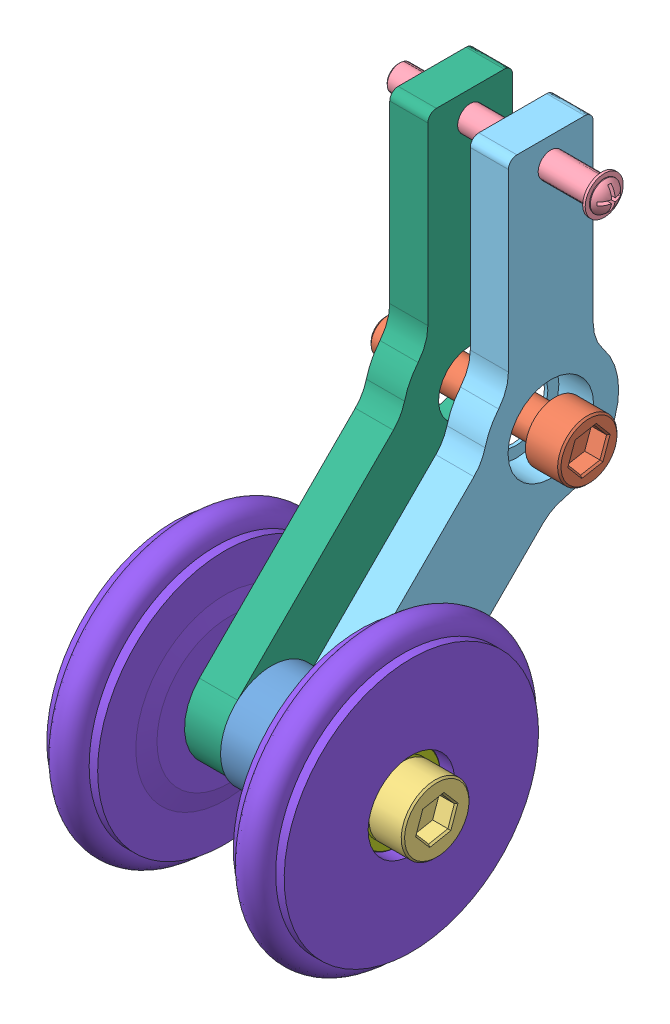
SolidWorks assembly 防震承重轮总成-左, configuration 默认. Lengths in mm.
Overall size (38 75.35 53.59).
10 component instances, 8 part files, 18 mates.
Components (placement in the parent):
- 摇臂间隔圈-1: 摇臂间隔圈 [默认] at (-107.9188 -3.5838 67.4738) x (1 0 0) z (0 -0.74001 0.672596) size (5 12 12)
- M4X20mm内六角螺钉-1: M4X20mm内六角螺钉 [默认] at (-97.9188 19.6326 44.0217) x (0 0.940827 -0.338887) z (0 -0.338887 -0.940827) size (7 24 7)
- M5X34mm内六角螺钉-1: M5X34mm内六角螺钉 [默认] at (-92.4188 -3.5838 67.4738) x (0 0.187145 -0.982332) z (0 -0.982332 -0.187145) size (8 38 8)
- M3X40圆头螺钉-1: M3X40圆头螺钉 [默认] at (-92.4188 46.6326 44.0217) x (1 0 0) z (0 0.998803 -0.048922) size (25.38 4.5 4.5)
- 减震轮摇臂-右-1: 减震轮摇臂-右 [默认] at (-100.6688 19.6326 44.0217) size (4.5 58.97 37.21)
- 减震轮摇臂-左-1: 减震轮摇臂-左 [默认] at (-110.1688 19.6326 44.0217) size (4.5 58.97 37.21)
- 5X10X4轴承-1: 5X10X4轴承 [默认] at (-96.9188 -3.5838 67.4738) size (4 10 10)
- 5X10X4轴承-2: 5X10X4轴承 [默认] at (-117.9188 -3.5838 67.4738) size (4 10 10)
- 防震承重轮-左右通用-1: 防震承重轮-左右通用 [默认] at (-91.4188 -3.5838 67.4738) x (-1 0 0) z (0 -0.924225 -0.381849) size (6.5 33.9 33.9)
- 防震承重轮-左右通用-2: 防震承重轮-左右通用 [默认] at (-119.4188 -3.5838 67.4738) size (6.5 33.9 33.9)
Mates (geometry in assembly coordinates):
- 重合4: coincident anti-aligned: plane of 摇臂间隔圈-1 through (-102.9188 -3.5838 67.4738) normal (1 0 0); plane of 减震轮摇臂-右-1 through (-102.9188 -3.341 67.231) normal (-1 0 0)
- 重合5: coincident anti-aligned: plane of 摇臂间隔圈-1 through (-107.9188 -3.5838 67.4738) normal (-1 0 0); plane of 减震轮摇臂-左-1 through (-107.9188 -3.341 67.231) normal (1 0 0)
- 同心29: concentric anti-aligned: cylinder of 5X10X4轴承-1 through (-92.9188 -3.5838 67.4738) axis (-1 0 0) radius 5; cylinder of 防震承重轮-左右通用-1 through (-91.4188 -3.5838 67.4738) axis (1 0 0) radius 5.1
- 重合6: coincident anti-aligned: plane of 5X10X4轴承-1 through (-96.9188 -3.5838 67.4738) normal (-1 0 0); plane of 防震承重轮-左右通用-1 through (-96.9188 -1.6364 62.7602) normal (1 0 0)
- 距离1: distance = 0.5 mm anti-aligned: plane of 减震轮摇臂-右-1 through (-98.4188 -3.341 67.231) normal (1 0 0); plane of 防震承重轮-左右通用-1 through (-97.9188 -0.3381 59.6179) normal (-1 0 0)
- 同心30: concentric aligned: cylinder of 5X10X4轴承-2 through (-113.9188 -3.5838 67.4738) axis (-1 0 0) radius 5; cylinder of 防震承重轮-左右通用-2 through (-119.4188 -3.5838 67.4738) axis (-1 0 0) radius 5.1
- 重合8: coincident anti-aligned: plane of 5X10X4轴承-2 through (-113.9188 -3.5838 67.4738) normal (1 0 0); plane of 防震承重轮-左右通用-2 through (-113.9188 1.5162 67.4738) normal (-1 0 0)
- 距离3: distance = 0.5 mm anti-aligned: plane of 防震承重轮-左右通用-2 through (-112.9188 4.9162 67.4738) normal (1 0 0); plane of 减震轮摇臂-左-1 through (-112.4188 -3.341 67.231) normal (-1 0 0)
- 同心32: concentric aligned: cylinder of M5X34mm内六角螺钉-1 through (-126.4188 -3.5838 67.4738) axis (1 0 0) radius 2.5; cylinder of 减震轮摇臂-左-1 through (-112.4188 -3.5838 67.4738) axis (1 0 0) radius 2.7
- 同心33: concentric anti-aligned: cylinder of M4X20mm内六角螺钉-1 through (-117.9188 19.6326 44.0217) axis (1 0 0) radius 2; cylinder of 减震轮摇臂-左-1 through (-108.3188 19.6326 44.0217) axis (-1 0 0) radius 5.05
- 同心34: concentric aligned: cylinder of M3X40圆头螺钉-1 through (-116.4188 46.6326 44.0217) axis (1 0 0) radius 1.5; cylinder of 减震轮摇臂-左-1 through (-113.9188 46.6326 44.0217) axis (1 0 0) radius 1.25
- 同心35: concentric anti-aligned: cylinder of 摇臂间隔圈-1 through (-102.9188 -3.5838 67.4738) axis (-1 0 0) radius 2.5; cylinder of 减震轮摇臂-右-1 through (-102.9188 -3.5838 67.4738) axis (1 0 0) radius 2.7
- 同心36: concentric anti-aligned: cylinder of 摇臂间隔圈-1 through (-102.9188 -3.5838 67.4738) axis (-1 0 0) radius 2.5; cylinder of 减震轮摇臂-左-1 through (-112.4188 -3.5838 67.4738) axis (1 0 0) radius 2.7
- 同心37: concentric anti-aligned: cylinder of 减震轮摇臂-左-1 through (-112.4188 -3.5838 67.4738) axis (1 0 0) radius 2.7; cylinder of 5X10X4轴承-2 through (-113.9188 -3.5838 67.4738) axis (-1 0 0) radius 2.5
- 同心38: concentric anti-aligned: circle of 5X10X4轴承-1; cylinder of 5X10X4轴承-2 through (-113.9188 -3.5838 67.4738) axis (-1 0 0) radius 2.5
- 距离4: distance = 0.5 mm anti-aligned: plane of 5X10X4轴承-1 through (-92.9188 -3.5838 67.4738) normal (1 0 0); plane of M5X34mm内六角螺钉-1 through (-92.4188 -3.5838 67.4738) normal (-1 0 0)
- 距离5: distance = 0.5 mm anti-aligned: plane of M4X20mm内六角螺钉-1 through (-97.9188 19.6326 44.0217) normal (-1 0 0); plane of 减震轮摇臂-右-1 through (-98.4188 -3.341 67.231) normal (1 0 0)
- 距离6: distance = 4 mm aligned: plane of M3X40圆头螺钉-1 through (-116.4188 46.6326 44.0217) normal (-1 0 0); plane of 减震轮摇臂-左-1 through (-112.4188 -3.341 67.231) normal (-1 0 0)
